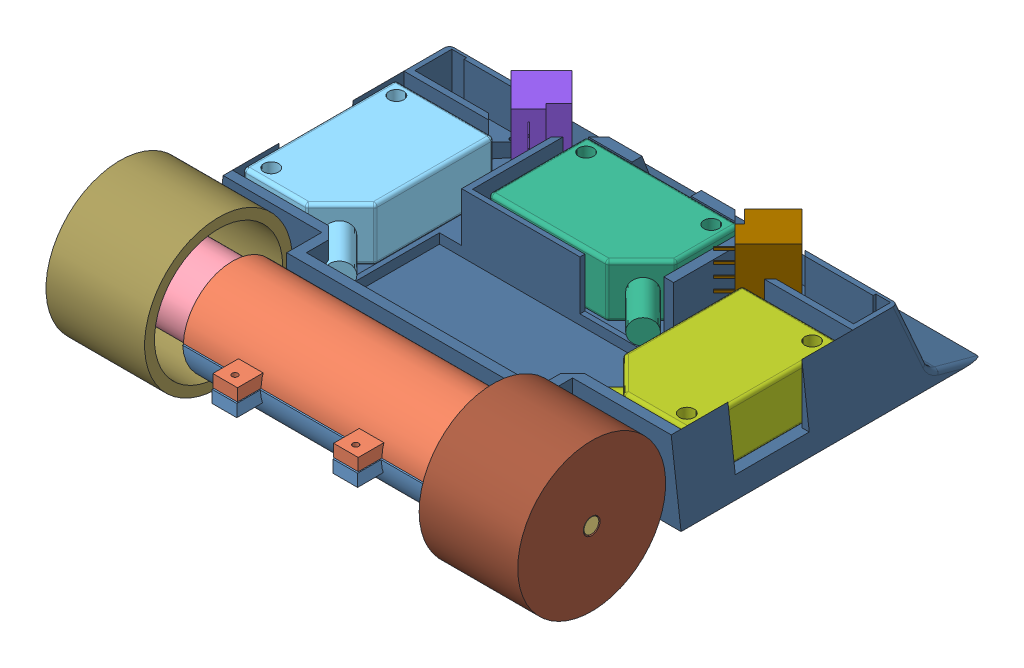
SolidWorks assembly asd, configuration Default. Lengths in mm.
Overall size (96.48 30.58 94.68).
12 component instances, 12 part files, 0 mates.
Components (placement in the parent):
- arka alt-1: arka alt [Default] at (-88.3935 43.8234 -22.4318) size (51 9.5 24.75)
- arka üst-1: arka üst [Default] at (-88.2888 43.1282 -22.4604) size (51 9.5 24.74)
- faullhabber-1: faullhabber [Default] at (-67.5582 24.5459 -53.9011) size (47.5 15 15)
- faullhabber - Copy-1: faullhabber - Copy [Default] at (-58.1158 25.1207 16.9682) x (-1 0 0) z (0 0 -1) size (47.5 15 15)
- omron4-1: omron4 [Default] at (-98.1381 49.8885 -55.9092) x (0 0 1) z (1 0 0) size (37.72 10.8 25.16)
- omron4 - Copy-1: omron4 - Copy [Default] at (-63.108 39.2325 -70.75) size (37.72 10.8 25.16)
- omron5-1: omron5 [Default] at (-27.783 38.1721 -55.863) x (0 0 1) z (-1 0 0) size (37.72 10.8 25.16)
- sharp - Copy-1: sharp - Copy [Default] at (-72.3093 48.1287 -71.3701) x (0.707107 0 0.707107) z (0 -1 0) size (12.7 8.7 15)
- sharp - Copy - Copy-1: sharp - Copy - Copy [Default] at (-53.3548 46.7455 -70.3044) x (-0.707107 0 0.707107) z (0 1 0) size (12.7 8.7 15)
- sharplı ön-1: sharplı ön [Default] at (-50.1396 34.9891 -28.7944) x (0 0 -1) z (1 0 0) size (68 16 95)
- tekerlek-1: tekerlek [Default] at (-34.9982 44.6046 -18.0801) size (20 30 30)
- tekerlek2-1: tekerlek2 [Default] at (-91.4738 45.1864 -18.8689) x (-1 0 0) z (0 0 -1) size (20 30 30)
